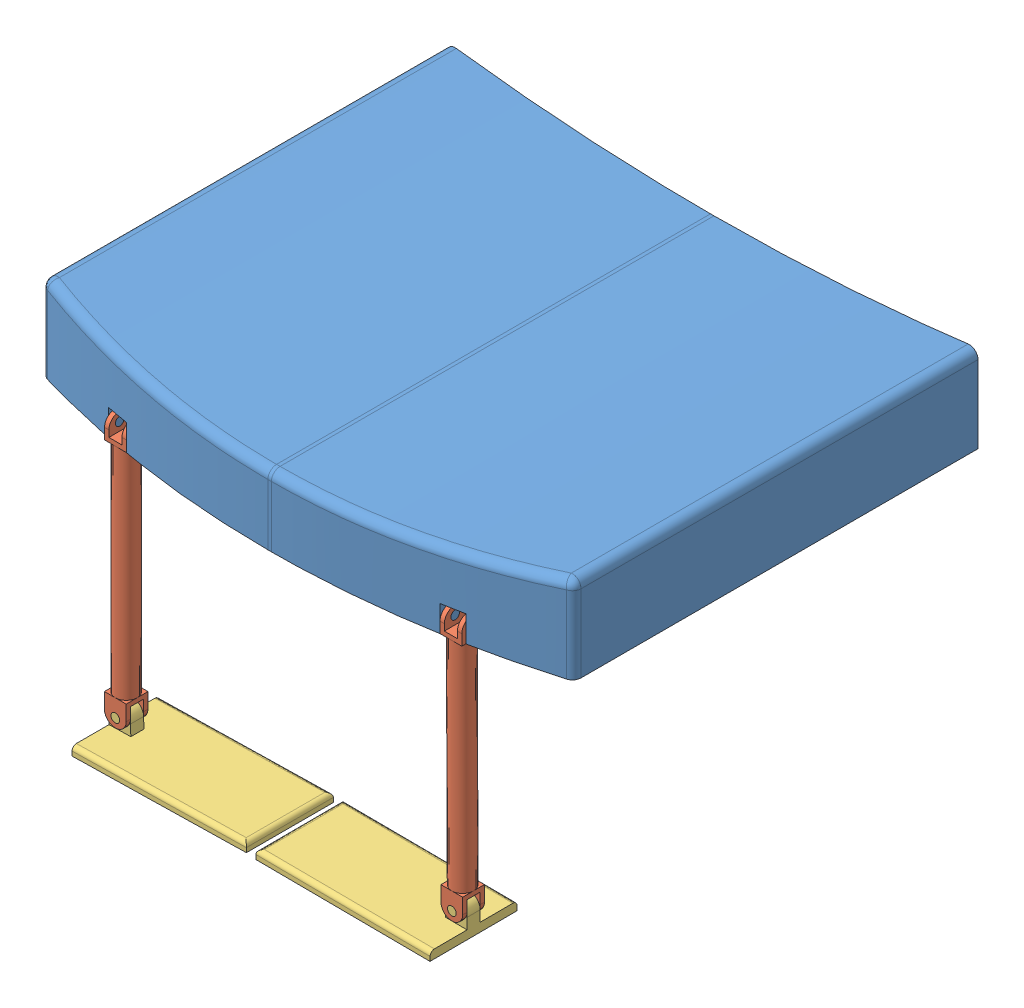
SolidWorks assembly Assem1, configuration Default. Lengths in mm.
Overall size (610 404.15 530.15).
5 component instances, 3 part files, 8 mates.
Components (placement in the parent):
- Bottom Rest-1: Bottom Rest [Default] at (302.6868 294.5233 402.6351) size (610 108.87 518.43)
- Connection Rods-1: Connection Rods [Default] at (110.1868 169.5233 628.7027) x (1 0 0) z (0 0.000483 1) size (25 305 25)
- Foot Rest-1: Foot Rest [Default] at (198.1713 1.286 628.784) x (0.999798 0.020088 -0.00001) z (0 0.000483 1) size (200 35 100)
- Foot Rest-2: Foot Rest [Default] at (407.5211 0.1128 627.4055) x (-0.999978 0.006704 0.000027) z (0 0.003974 -0.999992) size (200 35 100)
- Connection Rods-2: Connection Rods [Default] at (495.1868 169.5244 628.0787) x (1 0 0) z (0 -0.003974 0.999992) size (25 305 25)
Mates (geometry in assembly coordinates):
- Concentric2: concentric aligned: cylinder of Connection Rods-1 through (110.1868 24.5293 641.2728) axis (0 -0.000483 -1) radius 5; cylinder of Foot Rest-1 through (110.1868 24.5293 641.2728) axis (0 -0.000483 -1) radius 5
- Coincident2: coincident anti-aligned: plane of Connection Rods-1 through (97.6868 14.5269 636.2776) normal (0 -0.000483 -1); plane of Foot Rest-1 through (198.1713 1.2897 636.284) normal (0 0.000483 1)
- Concentric3: concentric aligned: cylinder of Bottom Rest-1 through (102.6868 309.5233 628.6351) axis (-1 0 0) radius 5; cylinder of Connection Rods-1 through (122.6868 309.5233 628.6351) axis (-1 0 0) radius 5
- Coincident6: coincident anti-aligned: plane of Bottom Rest-1 through (97.6868 324.5233 643.6351) normal (1 0 0); plane of Connection Rods-1 through (97.6868 299.5172 616.1399) normal (-1 0 0)
- Concentric8: concentric anti-aligned: cylinder of Bottom Rest-1 through (502.6868 309.5233 628.6351) axis (1 0 0) radius 5; cylinder of Connection Rods-2 through (507.6868 309.5233 628.6351) axis (-1 0 0) radius 5
- Coincident9: coincident anti-aligned: plane of Bottom Rest-1 through (507.6868 324.5233 643.6351) normal (-1 0 0); plane of Connection Rods-2 through (507.6868 299.573 616.0954) normal (1 0 0)
- Concentric9: concentric anti-aligned: cylinder of Foot Rest-2 through (495.1868 24.5752 615.0026) axis (0 -0.003974 0.999992) radius 5; cylinder of Connection Rods-2 through (495.1868 24.4758 640.0024) axis (0 0.003974 -0.999992) radius 5
- Coincident10: coincident anti-aligned: plane of Foot Rest-2 through (407.5211 0.083 634.9055) normal (0 -0.003974 0.999992); plane of Connection Rods-2 through (482.6868 14.4958 634.9627) normal (0 0.003974 -0.999992)
